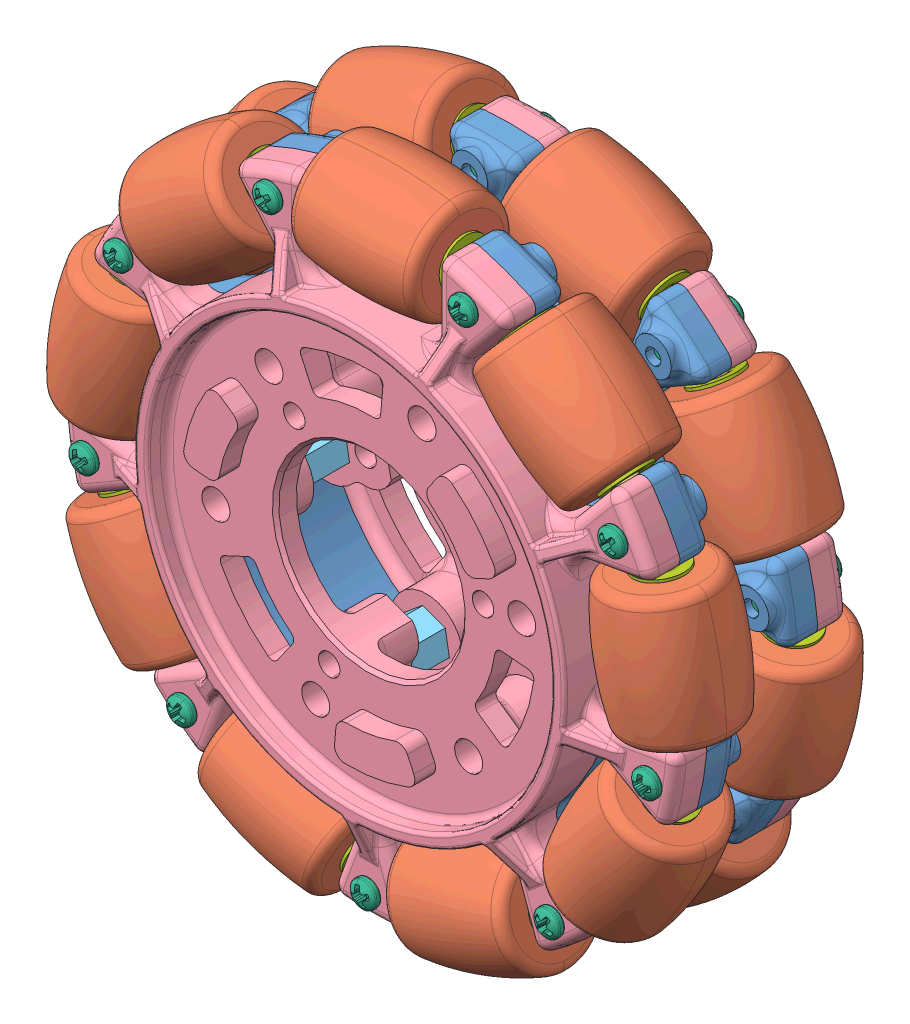
SolidWorks assembly omni, configuration Default. Lengths in mm.
Overall size (120.77 120.98 38.22).
99 component instances, 7 part files, 0 mates.
Components (placement in the parent):
- 217-2584-002 Rev2.STEP-1: 217-2584-002 Rev2.STEP [Default] at origin size (94.13 94.49 23.37)
- 217-2584-001 Rev1.STEP-1: 217-2584-001 Rev1.STEP [Default] at (0 42.2261 8.4469) x (1 0 0) z (0 0.098272 -0.99516) size (19.3 17.24 17.24)
- 217-2584-001 Rev1.STEP-2: 217-2584-001 Rev1.STEP [Default] at (14.3997 39.5628 -8.4469) x (0.939693 -0.34202 0) z (0.288806 0.793488 0.535694) size (19.3 17.24 17.24)
- 217-2584-004 Rev1.STEP-1: 217-2584-004 Rev1.STEP [Default] at (36.3978 21.1609 -8.4469) x (0.5 -0.866025 0) z (0.824389 0.475961 0.306341) size (25.4 3 3)
- 217-2584-004 Rev1.STEP-2: 217-2584-004 Rev1.STEP [Default] at (27.2397 32.2654 8.4469) x (0.766044 -0.642788 0) z (-0.338976 -0.403976 0.849646) size (25.4 3 3)
- 217-2584-004 Rev1.STEP-3: 217-2584-004 Rev1.STEP [Default] at (41.4843 -7.1858 -8.4469) x (-0.173648 -0.984808 0) z (0.93746 -0.1653 0.306341) size (25.4 3 3)
- 217-2584-004 Rev1.STEP-4: 217-2584-004 Rev1.STEP [Default] at (27.1599 -32.1703 -8.4469) x (-0.766044 -0.642788 0) z (0.611884 -0.729215 0.306341) size (25.4 3 3)
- 217-2584-004 Rev1.STEP-5: 217-2584-004 Rev1.STEP [Default] at (0.127 -42.1019 -8.4469) x (-1 0 0) z (0 -0.951922 0.306341) size (25.4 3 3)
- 217-2584-004 Rev1.STEP-6: 217-2584-004 Rev1.STEP [Default] at (-26.9653 -32.3336 -8.4469) x (-0.766044 0.642788 0) z (-0.611884 -0.729215 0.306341) size (25.4 3 3)
- 217-2584-004 Rev1.STEP-7: 217-2584-004 Rev1.STEP [Default] at (-41.4402 -7.436 -8.4469) x (-0.173648 0.984808 0) z (-0.93746 -0.1653 0.306341) size (25.4 3 3)
- 217-2584-004 Rev1.STEP-8: 217-2584-004 Rev1.STEP [Default] at (-36.5248 20.941 -8.4469) x (0.5 0.866025 0) z (-0.824389 0.475961 0.306341) size (25.4 3 3)
- 217-2584-004 Rev1.STEP-9: 217-2584-004 Rev1.STEP [Default] at (-14.519 39.5194 -8.4469) x (0.939693 0.34202 0) z (-0.325576 0.894514 0.306341) size (25.4 3 3)
- 217-2584-004 Rev1.STEP-10: 217-2584-004 Rev1.STEP [Default] at (14.2804 39.6063 -8.4469) x (0.939693 -0.34202 0) z (0.325576 0.894514 0.306341) size (25.4 3 3)
- 217-2584-004 Rev1.STEP-11: 217-2584-004 Rev1.STEP [Default] at (41.6066 7.2074 8.4469) x (0.173648 -0.984808 0) z (-0.519342 -0.091574 0.849646) size (25.4 3 3)
- 217-2584-004 Rev1.STEP-12: 217-2584-004 Rev1.STEP [Default] at (36.5054 -21.223 8.4469) x (-0.5 -0.866025 0) z (-0.456702 0.263677 0.849646) size (25.4 3 3)
- 217-2584-004 Rev1.STEP-13: 217-2584-004 Rev1.STEP [Default] at (14.3228 -39.723 8.4469) x (-0.939693 -0.34202 0) z (-0.180366 0.49555 0.849646) size (25.4 3 3)
- 217-2584-004 Rev1.STEP-14: 217-2584-004 Rev1.STEP [Default] at (-14.5615 -39.6361 8.4469) x (-0.939693 0.34202 0) z (0.180366 0.49555 0.849646) size (25.4 3 3)
- 217-2584-004 Rev1.STEP-15: 217-2584-004 Rev1.STEP [Default] at (-36.6324 -21.0031 8.4469) x (-0.5 0.866025 0) z (0.456702 0.263677 0.849646) size (25.4 3 3)
- 217-2584-004 Rev1.STEP-16: 217-2584-004 Rev1.STEP [Default] at (-41.5625 7.4576 8.4469) x (0.173648 0.984808 0) z (0.519342 -0.091574 0.849646) size (25.4 3 3)
- 217-2584-004 Rev1.STEP-17: 217-2584-004 Rev1.STEP [Default] at (-27.0451 32.4287 8.4469) x (0.766044 0.642788 0) z (0.338976 -0.403976 0.849646) size (25.4 3 3)
- 217-2584-004 Rev1.STEP-18: 217-2584-004 Rev1.STEP [Default] at (0.127 42.2261 8.4469) x (1 0 0) z (0 -0.527354 0.849646) size (25.4 3 3)
- 217-2584-001 Rev1.STEP-3: 217-2584-001 Rev1.STEP [Default] at (27.1424 32.3471 8.4469) x (0.766044 -0.642788 0) z (0.063168 0.075281 -0.99516) size (19.3 17.24 17.24)
- 217-2584-001 Rev1.STEP-4: 217-2584-001 Rev1.STEP [Default] at (41.5846 7.3325 8.4469) x (0.173648 -0.984808 0) z (0.096779 0.017065 -0.99516) size (19.3 17.24 17.24)
- 217-2584-001 Rev1.STEP-5: 217-2584-001 Rev1.STEP [Default] at (36.5689 -21.1131 8.4469) x (-0.5 -0.866025 0) z (0.085106 -0.049136 -0.99516) size (19.3 17.24 17.24)
- 217-2584-001 Rev1.STEP-6: 217-2584-001 Rev1.STEP [Default] at (14.4422 -39.6796 8.4469) x (-0.939693 -0.34202 0) z (0.033611 -0.092346 -0.99516) size (19.3 17.24 17.24)
- 217-2584-001 Rev1.STEP-7: 217-2584-001 Rev1.STEP [Default] at (-14.4422 -39.6796 8.4469) x (-0.939693 0.34202 0) z (-0.033611 -0.092346 -0.99516) size (19.3 17.24 17.24)
- 217-2584-001 Rev1.STEP-8: 217-2584-001 Rev1.STEP [Default] at (-36.5689 -21.1131 8.4469) x (-0.5 0.866025 0) z (-0.085106 -0.049136 -0.99516) size (19.3 17.24 17.24)
- 217-2584-001 Rev1.STEP-9: 217-2584-001 Rev1.STEP [Default] at (-41.5846 7.3325 8.4469) x (0.173648 0.984808 0) z (-0.096779 0.017065 -0.99516) size (19.3 17.24 17.24)
- 217-2584-001 Rev1.STEP-10: 217-2584-001 Rev1.STEP [Default] at (-27.1424 32.3471 8.4469) x (0.766044 0.642788 0) z (-0.063168 0.075281 -0.99516) size (19.3 17.24 17.24)
- 217-2584-001 Rev1.STEP-11: 217-2584-001 Rev1.STEP [Default] at (36.4613 21.051 -8.4469) x (0.5 -0.866025 0) z (0.731282 0.422206 0.535694) size (19.3 17.24 17.24)
- 217-2584-001 Rev1.STEP-12: 217-2584-001 Rev1.STEP [Default] at (41.4623 -7.3109 -8.4469) x (-0.173648 -0.984808 0) z (0.831584 -0.146631 0.535694) size (19.3 17.24 17.24)
- 217-2584-001 Rev1.STEP-13: 217-2584-001 Rev1.STEP [Default] at (27.0626 -32.2519 -8.4469) x (-0.766044 -0.642788 0) z (0.542778 -0.646857 0.535694) size (19.3 17.24 17.24)
- 217-2584-001 Rev1.STEP-14: 217-2584-001 Rev1.STEP [Default] at (0 -42.1019 -8.4469) x (-1 0 0) z (0 -0.844412 0.535694) size (19.3 17.24 17.24)
- 217-2584-001 Rev1.STEP-15: 217-2584-001 Rev1.STEP [Default] at (-27.0626 -32.2519 -8.4469) x (-0.766044 0.642788 0) z (-0.542778 -0.646857 0.535694) size (19.3 17.24 17.24)
- 217-2584-001 Rev1.STEP-16: 217-2584-001 Rev1.STEP [Default] at (-41.4623 -7.3109 -8.4469) x (-0.173648 0.984808 0) z (-0.831584 -0.146631 0.535694) size (19.3 17.24 17.24)
- 217-2584-001 Rev1.STEP-17: 217-2584-001 Rev1.STEP [Default] at (-36.4613 21.051 -8.4469) x (0.5 0.866025 0) z (-0.731282 0.422206 0.535694) size (19.3 17.24 17.24)
- 217-2584-001 Rev1.STEP-18: 217-2584-001 Rev1.STEP [Default] at (-14.3997 39.5628 -8.4469) x (0.939693 0.34202 0) z (-0.288806 0.793488 0.535694) size (19.3 17.24 17.24)
- 217-2584-003 Rev4.STEP-1: 217-2584-003 Rev4.STEP [Default] at (0 0 -10.0965) x (-0.939693 0.34202 0) z (0 0 -1) size (94.13 92.92 12.7)
- 217-2584-003 Rev4.STEP-2: 217-2584-003 Rev4.STEP [Default] at (0 0 10.0965) x (-0.939693 0.34202 0) z (0 0 1) size (94.13 92.92 12.7)
- BEAM-0750.STEP-1: BEAM-0750.STEP [Default] at (-23.4507 -4.135 0.127) x (0.173648 -0.984808 0) z (-0.984808 -0.173648 0) size (7.34 19.05 7.34)
- BEAM-0750.STEP-2: BEAM-0750.STEP [Default] at (-8.1444 -22.3764 0.127) x (0.939693 -0.34202 0) z (-0.34202 -0.939693 0) size (7.34 19.05 7.34)
- BEAM-0750.STEP-3: BEAM-0750.STEP [Default] at (15.3064 -18.2414 0.127) x (0.766044 0.642788 0) z (0.642788 -0.766044 0) size (7.34 19.05 7.34)
- BEAM-0750.STEP-4: BEAM-0750.STEP [Default] at (23.4507 4.135 0.127) x (-0.173648 0.984808 0) z (0.984808 0.173648 0) size (7.34 19.05 7.34)
- BEAM-0750.STEP-5: BEAM-0750.STEP [Default] at (8.1444 22.3764 0.127) x (-0.939693 0.34202 0) z (0.34202 0.939693 0) size (7.34 19.05 7.34)
- BEAM-0750.STEP-6: BEAM-0750.STEP [Default] at (-15.3064 18.2414 0.127) x (-0.766044 -0.642788 0) z (-0.642788 0.766044 0) size (7.34 19.05 7.34)
- 90116A020_90116A020.STEP-1: 90116A020_90116A020.STEP [Default] at (0 43.815 -3.2715) x (-0.923728 -0.383049 0) z (0 0 -1) size (4 4 11.61)
- 90116A020_90116A020.STEP-2: 90116A020_90116A020.STEP [Default] at (14.9856 41.1726 3.2715) x (0.999999 0.001318 0) z (0 0 1) size (4 4 11.61)
- 90116A020_90116A020.STEP-3: 90116A020_90116A020.STEP [Default] at (-14.9856 41.1726 3.2715) x (0.765196 0.643797 0) z (0 0 1) size (4 4 11.61)
- 90116A020_90116A020.STEP-4: 90116A020_90116A020.STEP [Default] at (-37.9449 21.9075 3.2715) x (0.17235 0.985036 0) z (0 0 1) size (4 4 11.61)
- 90116A020_90116A020.STEP-5: 90116A020_90116A020.STEP [Default] at (-43.1494 -7.6084 3.2715) x (-0.501141 0.865366 0) z (0 0 1) size (4 4 11.61)
- 90116A020_90116A020.STEP-6: 90116A020_90116A020.STEP [Default] at (-28.1637 -33.5642 3.2715) x (-0.940143 0.340781 0) z (0 0 1) size (4 4 11.61)
- 90116A020_90116A020.STEP-7: 90116A020_90116A020.STEP [Default] at (0 -43.815 3.2715) x (-0.939241 -0.343259 0) z (0 0 1) size (4 4 11.61)
- 90116A020_90116A020.STEP-8: 90116A020_90116A020.STEP [Default] at (28.1637 -33.5642 3.2715) x (-0.498858 -0.866684 0) z (0 0 1) size (4 4 11.61)
- 90116A020_90116A020.STEP-9: 90116A020_90116A020.STEP [Default] at (43.1494 -7.6084 3.2715) x (0.174946 -0.984578 0) z (0 0 1) size (4 4 11.61)
- 90116A020_90116A020.STEP-10: 90116A020_90116A020.STEP [Default] at (37.9449 21.9075 3.2715) x (0.766891 -0.641777 0) z (0 0 1) size (4 4 11.61)
- 90116A020_90116A020.STEP-11: 90116A020_90116A020.STEP [Default] at (-28.1637 33.5642 -3.2715) x (-0.461398 -0.887193 0) z (0 0 -1) size (4 4 11.61)
- 90116A020_90116A020.STEP-12: 90116A020_90116A020.STEP [Default] at (-43.1494 7.6084 -3.2715) x (0.216826 -0.97621 0) z (0 0 -1) size (4 4 11.61)
- 90116A020_90116A020.STEP-13: 90116A020_90116A020.STEP [Default] at (-37.9449 -21.9075 -3.2715) x (0.793594 -0.608447 0) z (0 0 -1) size (4 4 11.61)
- 90116A020_90116A020.STEP-14: 90116A020_90116A020.STEP [Default] at (-14.9856 -41.1726 -3.2715) x (0.999031 0.044015 0) z (0 0 -1) size (4 4 11.61)
- 90116A020_90116A020.STEP-15: 90116A020_90116A020.STEP [Default] at (14.9856 -41.1726 -3.2715) x (0.73701 0.675882 0) z (0 0 -1) size (4 4 11.61)
- 90116A020_90116A020.STEP-16: 90116A020_90116A020.STEP [Default] at (37.9449 -21.9075 -3.2715) x (0.130134 0.991496 0) z (0 0 -1) size (4 4 11.61)
- 90116A020_90116A020.STEP-17: 90116A020_90116A020.STEP [Default] at (43.1494 7.6084 -3.2715) x (-0.537633 0.843179 0) z (0 0 -1) size (4 4 11.61)
- 90116A020_90116A020.STEP-18: 90116A020_90116A020.STEP [Default] at (28.1637 33.5642 -3.2715) x (-0.953836 0.300328 0) z (0 0 -1) size (4 4 11.61)
- 217-2584-005 Rev1 A.STEP-1: 217-2584-005 Rev1 A.STEP [Default] at (18.9943 37.8905 -8.4469) x (0.289365 0.795024 -0.533108) z (0.939693 -0.34202 0) size (7.38 7.38 9.92)
- 217-2584-005 Rev1 A.STEP-2: 217-2584-005 Rev1 A.STEP [Default] at (9.8051 41.2352 -8.4469) x (0.005632 0.015473 -0.999864) z (-0.939693 0.34202 0) size (7.38 7.38 9.92)
- 217-2584-005 Rev1 A.STEP-3: 217-2584-005 Rev1 A.STEP [Default] at (34.0166 25.2854 -8.4469) x (0.01426 0.008233 -0.999864) z (-0.5 0.866025 0) size (7.38 7.38 9.92)
- 217-2584-005 Rev1 A.STEP-4: 217-2584-005 Rev1 A.STEP [Default] at (42.3113 -2.4957 -8.4469) x (0.016216 -0.002859 -0.999864) z (0.173648 0.984808 0) size (7.38 7.38 9.92)
- 217-2584-005 Rev1 A.STEP-5: 217-2584-005 Rev1 A.STEP [Default] at (30.8082 -29.109 -8.4469) x (0.010584 -0.012614 -0.999864) z (0.766044 0.642788 0) size (7.38 7.38 9.92)
- 217-2584-005 Rev1 A.STEP-6: 217-2584-005 Rev1 A.STEP [Default] at (4.8895 -42.1019 -8.4469) x (0 -0.016466 -0.999864) z (1 0 0) size (7.38 7.38 9.92)
- 217-2584-005 Rev1 A.STEP-7: 217-2584-005 Rev1 A.STEP [Default] at (-23.317 -35.3948 -8.4469) x (-0.010584 -0.012614 -0.999864) z (0.766044 -0.642788 0) size (7.38 7.38 9.92)
- 217-2584-005 Rev1 A.STEP-8: 217-2584-005 Rev1 A.STEP [Default] at (-40.6132 -12.1261 -8.4469) x (-0.016216 -0.002859 -0.999864) z (0.173648 -0.984808 0) size (7.38 7.38 9.92)
- 217-2584-005 Rev1 A.STEP-9: 217-2584-005 Rev1 A.STEP [Default] at (-38.9061 16.8165 -8.4469) x (-0.01426 0.008233 -0.999864) z (-0.5 -0.866025 0) size (7.38 7.38 9.92)
- 217-2584-005 Rev1 A.STEP-10: 217-2584-005 Rev1 A.STEP [Default] at (-18.9943 37.8905 -8.4469) x (-0.005632 0.015473 -0.999864) z (-0.939693 -0.34202 0) size (7.38 7.38 9.92)
- 217-2584-005 Rev1 A.STEP-11: 217-2584-005 Rev1 A.STEP [Default] at (38.9061 16.8165 -8.4469) x (0.732698 0.423024 -0.533108) z (0.5 -0.866025 0) size (7.38 7.38 9.92)
- 217-2584-005 Rev1 A.STEP-12: 217-2584-005 Rev1 A.STEP [Default] at (40.6132 -12.1261 -8.4469) x (0.833194 -0.146915 -0.533108) z (-0.173648 -0.984808 0) size (7.38 7.38 9.92)
- 217-2584-005 Rev1 A.STEP-13: 217-2584-005 Rev1 A.STEP [Default] at (23.317 -35.3948 -8.4469) x (0.543829 -0.64811 -0.533108) z (-0.766044 -0.642788 0) size (7.38 7.38 9.92)
- 217-2584-005 Rev1 A.STEP-14: 217-2584-005 Rev1 A.STEP [Default] at (-4.8895 -42.1019 -8.4469) x (0 -0.846047 -0.533108) z (-1 0 0) size (7.38 7.38 9.92)
- 217-2584-005 Rev1 A.STEP-15: 217-2584-005 Rev1 A.STEP [Default] at (-30.8082 -29.109 -8.4469) x (-0.543829 -0.64811 -0.533108) z (-0.766044 0.642788 0) size (7.38 7.38 9.92)
- 217-2584-005 Rev1 A.STEP-16: 217-2584-005 Rev1 A.STEP [Default] at (-42.3113 -2.4957 -8.4469) x (-0.833194 -0.146915 -0.533108) z (-0.173648 0.984808 0) size (7.38 7.38 9.92)
- 217-2584-005 Rev1 A.STEP-17: 217-2584-005 Rev1 A.STEP [Default] at (-34.0166 25.2854 -8.4469) x (-0.732698 0.423024 -0.533108) z (0.5 0.866025 0) size (7.38 7.38 9.92)
- 217-2584-005 Rev1 A.STEP-18: 217-2584-005 Rev1 A.STEP [Default] at (-9.8051 41.2352 -8.4469) x (-0.289365 0.795024 -0.533108) z (0.939693 0.34202 0) size (7.38 7.38 9.92)
- 217-2584-005 Rev1 A.STEP-19: 217-2584-005 Rev1 A.STEP [Default] at (4.8895 42.2261 8.4469) x (0 -0.427737 -0.903903) z (1 0 0) size (7.38 7.38 9.92)
- 217-2584-005 Rev1 A.STEP-20: 217-2584-005 Rev1 A.STEP [Default] at (-4.8895 42.2261 8.4469) x (0 0.672079 0.74048) z (-1 0 0) size (7.38 7.38 9.92)
- 217-2584-005 Rev1 A.STEP-21: 217-2584-005 Rev1 A.STEP [Default] at (23.3968 35.49 8.4469) x (0.432004 0.514842 0.74048) z (-0.766044 0.642788 0) size (7.38 7.38 9.92)
- 217-2584-005 Rev1 A.STEP-22: 217-2584-005 Rev1 A.STEP [Default] at (40.7355 12.1477 8.4469) x (0.661868 0.116705 0.74048) z (-0.173648 0.984808 0) size (7.38 7.38 9.92)
- 217-2584-005 Rev1 A.STEP-23: 217-2584-005 Rev1 A.STEP [Default] at (39.0136 -16.8786 8.4469) x (0.582037 -0.336039 0.74048) z (0.5 0.866025 0) size (7.38 7.38 9.92)
- 217-2584-005 Rev1 A.STEP-24: 217-2584-005 Rev1 A.STEP [Default] at (19.0368 -38.0072 8.4469) x (0.229864 -0.631547 0.74048) z (0.939693 0.34202 0) size (7.38 7.38 9.92)
- 217-2584-005 Rev1 A.STEP-25: 217-2584-005 Rev1 A.STEP [Default] at (-9.8475 -41.3519 8.4469) x (-0.229864 -0.631547 0.74048) z (0.939693 -0.34202 0) size (7.38 7.38 9.92)
- 217-2584-005 Rev1 A.STEP-26: 217-2584-005 Rev1 A.STEP [Default] at (-34.1241 -25.3475 8.4469) x (-0.582037 -0.336039 0.74048) z (0.5 -0.866025 0) size (7.38 7.38 9.92)
- 217-2584-005 Rev1 A.STEP-27: 217-2584-005 Rev1 A.STEP [Default] at (-42.4336 2.5173 8.4469) x (-0.661868 0.116705 0.74048) z (-0.173648 -0.984808 0) size (7.38 7.38 9.92)
- 217-2584-005 Rev1 A.STEP-28: 217-2584-005 Rev1 A.STEP [Default] at (-30.888 29.2042 8.4469) x (-0.432004 0.514842 0.74048) z (-0.766044 -0.642788 0) size (7.38 7.38 9.92)
- 217-2584-005 Rev1 A.STEP-29: 217-2584-005 Rev1 A.STEP [Default] at (30.888 29.2042 8.4469) x (-0.274944 -0.327665 -0.903903) z (0.766044 -0.642788 0) size (7.38 7.38 9.92)
- 217-2584-005 Rev1 A.STEP-30: 217-2584-005 Rev1 A.STEP [Default] at (42.4336 2.5173 8.4469) x (-0.421239 -0.074276 -0.903903) z (0.173648 -0.984808 0) size (7.38 7.38 9.92)
- 217-2584-005 Rev1 A.STEP-31: 217-2584-005 Rev1 A.STEP [Default] at (34.1241 -25.3475 8.4469) x (-0.370431 0.213868 -0.903903) z (-0.5 -0.866025 0) size (7.38 7.38 9.92)
- 217-2584-005 Rev1 A.STEP-32: 217-2584-005 Rev1 A.STEP [Default] at (9.8475 -41.3519 8.4469) x (-0.146295 0.401941 -0.903903) z (-0.939693 -0.34202 0) size (7.38 7.38 9.92)
- 217-2584-005 Rev1 A.STEP-33: 217-2584-005 Rev1 A.STEP [Default] at (-19.0368 -38.0072 8.4469) x (0.146295 0.401941 -0.903903) z (-0.939693 0.34202 0) size (7.38 7.38 9.92)
- 217-2584-005 Rev1 A.STEP-34: 217-2584-005 Rev1 A.STEP [Default] at (-39.0136 -16.8786 8.4469) x (0.370431 0.213868 -0.903903) z (-0.5 0.866025 0) size (7.38 7.38 9.92)
- 217-2584-005 Rev1 A.STEP-35: 217-2584-005 Rev1 A.STEP [Default] at (-40.7355 12.1477 8.4469) x (0.421239 -0.074276 -0.903903) z (0.173648 0.984808 0) size (7.38 7.38 9.92)
- 217-2584-005 Rev1 A.STEP-36: 217-2584-005 Rev1 A.STEP [Default] at (-23.3968 35.49 8.4469) x (0.274944 -0.327665 -0.903903) z (0.766044 0.642788 0) size (7.38 7.38 9.92)
